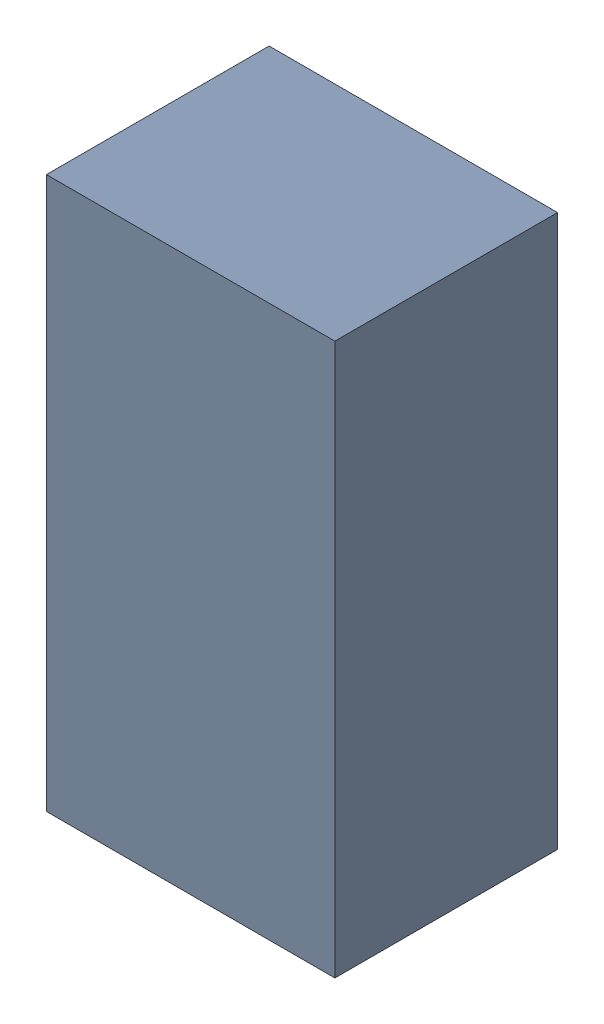
SolidWorks assembly 6327396544, configuration Default. Lengths in mm.
Overall size (0.33 0.63 0.25).
2 component instances, 1 part files, 0 mates.
Components (placement in the parent):
- 6701982208-1:  [Default] at (27.7 14.8 0) (suppressed, hidden)
- Extruded-1-1: Extruded-1 [Default] at origin size (0.33 0.63 0.25)
